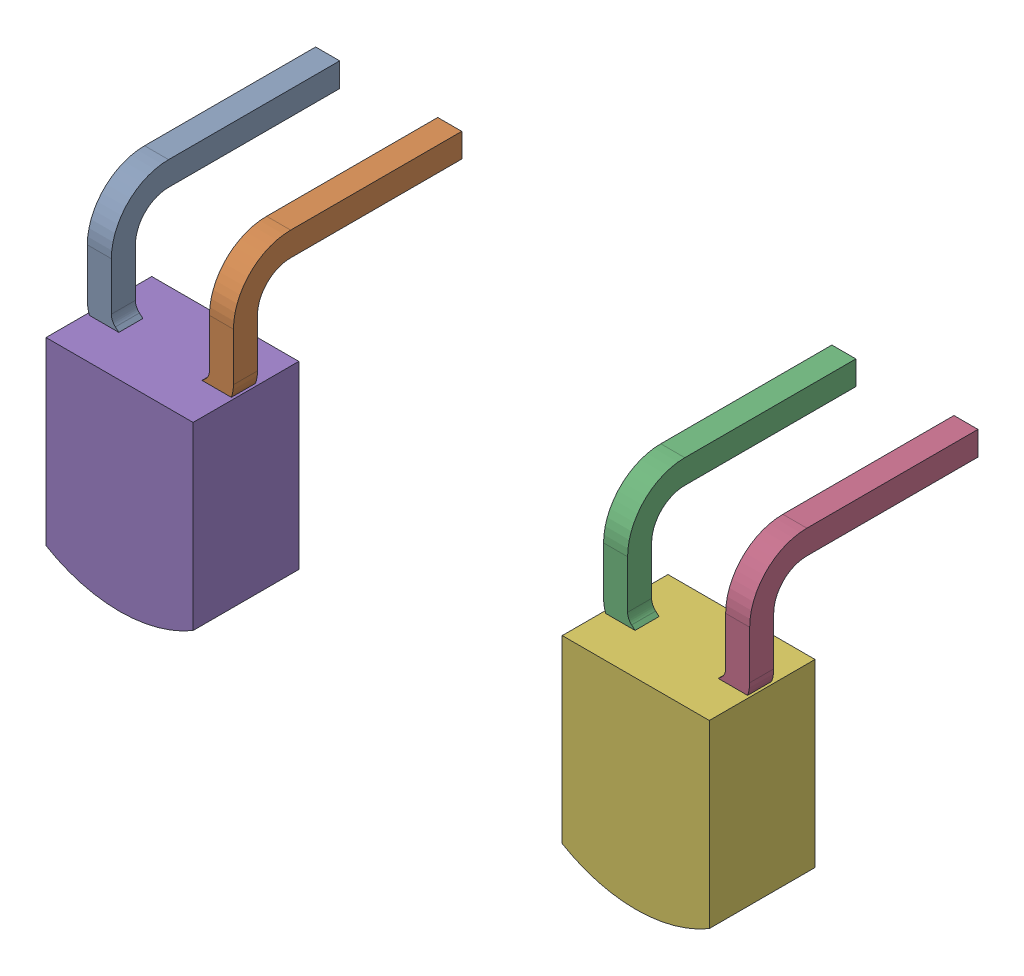
SolidWorks assembly lights.stp, configuration Default. Lengths in mm.
Overall size (13.8 6.61 5.6).
4 component instances, 3 part files, 0 mates.
Components (placement in the parent):
- led_org.stp-1: led_org.stp [Default] at (-5.37 0 2.2) size (3.04 5.2 4.86)
- led_org.stp-2: led_org.stp [Default] at (5.37 0 2.2) size (3.04 5.2 4.86)
- lights-0.stp-1: lights-0.stp [Default] at origin size (3.06 4.17 2.2)
- lights-1.stp-1: lights-1.stp [Default] at origin size (3.06 4.17 2.2)
